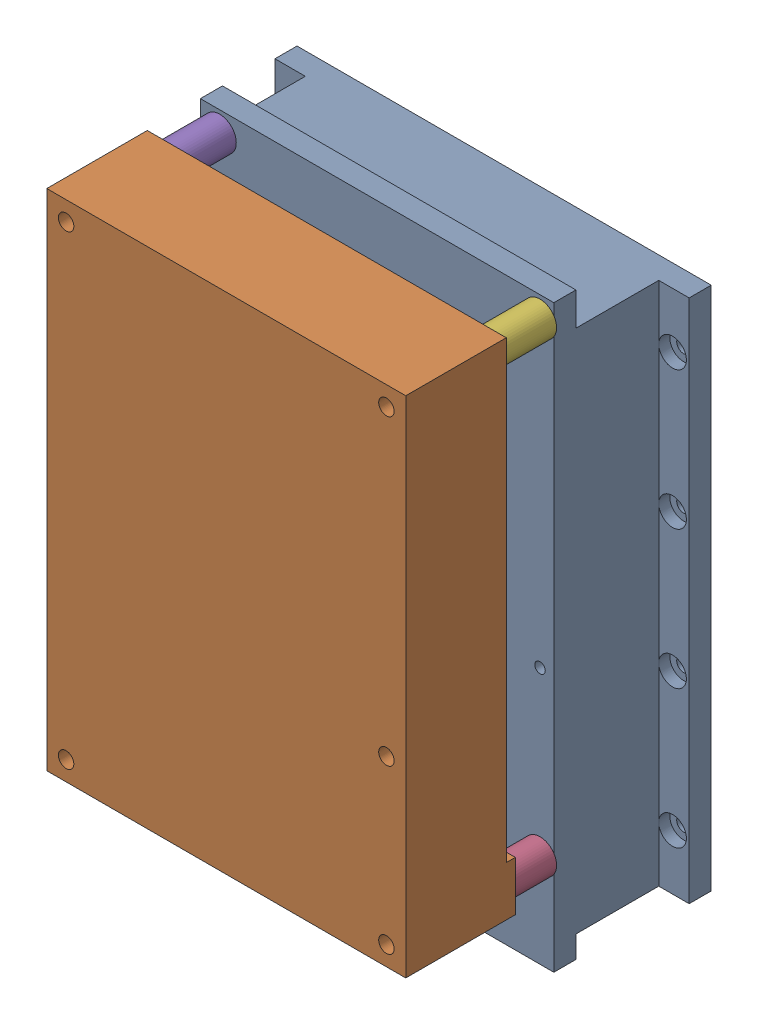
SolidWorks assembly assembly_slm_openSIM_V2.0, configuration Default. Lengths in mm.
Overall size (75 106.1 50.81).
6 component instances, 4 part files, 9 mates.
Components (placement in the parent):
- SLM_holder_openSIM_V2.0-1: SLM_holder_openSIM_V2.0 [Default] at (-2.8896 -11.8351 70.8026) size (75 105 23)
- SLM_Model_Folded_openSIM_V2.0-1: SLM_Model_Folded_openSIM_V2.0 [Default] at (33.2728 54.1041 103.415) size (65 105.91 35.45)
- SP-J3-8_20200728_openSIM_V2.0-1: SP-J3-8_20200728_openSIM_V2.0 [Default] at (6.1104 1.1749 93.8026) size (6 6 8)
- SP-J3-8_20200728_openSIM_V2.0-2: SP-J3-8_20200728_openSIM_V2.0 [Default] at (64.1104 1.1749 93.8026) size (6 6 8)
- SP-J3-10_20200728_openSIM_V2.0-1: SP-J3-10_20200728_openSIM_V2.0 [Default] at (6.1104 85.4749 93.8026) size (6 6 10)
- SP-J3-10_20200728_openSIM_V2.0-2: SP-J3-10_20200728_openSIM_V2.0 [Default] at (64.1104 85.4749 93.8026) size (6 6 10)
Mates (geometry in assembly coordinates):
- Coincident5: coincident aligned: plane of SLM_holder_20200728-1 through (-2.8896 -11.8351 93.8026) normal (0 0 1); circle of SP-J3-8_20200728-1
- Concentric5: concentric anti-aligned: circle of SLM_holder_20200728-1; circle of SP-J3-8_20200728-1
- Coincident8: coincident anti-aligned: plane of SLM_holder_20200728-1 through (-2.8896 -11.8351 93.8026) normal (0 0 1); plane of SP-J3-8_20200728-2 through (64.1104 1.1749 93.8026) normal (0 0 -1)
- Concentric6: concentric anti-aligned: circle of SLM_holder_20200728-1; circle of SP-J3-8_20200728-2
- Coincident10: coincident anti-aligned: plane of SLM_holder_20200728-1 through (-2.8896 -11.8351 93.8026) normal (0 0 1); plane of SP-J3-10_20200728-1 through (6.1104 85.4749 93.8026) normal (0 0 -1)
- Concentric7: concentric anti-aligned: circle of SLM_holder_20200728-1; circle of SP-J3-10_20200728-1
- Coincident11: coincident anti-aligned: plane of SLM_holder_20200728-1 through (-2.8896 -11.8351 93.8026) normal (0 0 1); plane of SP-J3-10_20200728-2 through (64.1104 85.4749 93.8026) normal (0 0 -1)
- Concentric8: concentric anti-aligned: circle of SLM_holder_20200728-1; circle of SP-J3-10_20200728-2
- Concentric9: concentric aligned: circle of SLM_Model_Folded_20200728-1; circle of SP-J3-8_20200728-2
